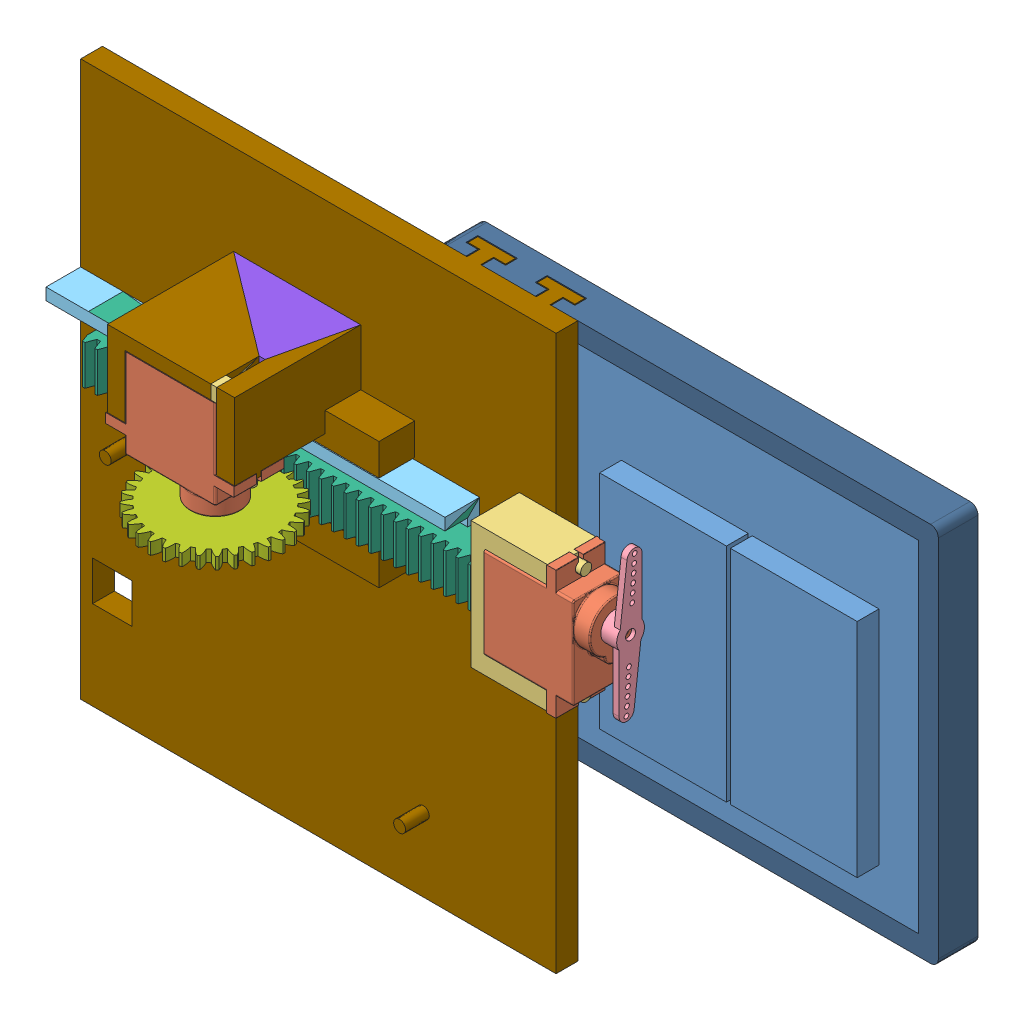
SolidWorks assembly 装配体3, configuration 默认. Lengths in mm.
Overall size (211 140 65.05).
16 component instances, 13 part files, 28 mates.
Components (placement in the parent):
- 底座框架-1: 底座框架 [默认] at (39.9503 -6.2034 133) size (126 96 10) (hidden)
- 活动底板-1: 活动底板 [默认] at origin size (120 140 23.5) (hidden)
- 开关建模-1: 开关建模 [默认] at (39.9503 -6.2034 133) size (86 86 15.5)
- SG90_Model_B.step-1: SG90_Model_B.step [默认] at (-8.8492 -13.8034 144.6) x (0 0 1) z (-1 0 0) size (12.61 32.4 29.2)
- 舵机外壳-1: 舵机外壳 [默认] at (-8.8492 -13.7034 138.5) x (0 -1 0) z (0 0 1) size (32.1 23 12.2)
- rack spur rectangular_gb-1: rack spur rectangular_gb [GB - Rack-spur - rectangular 1M 20PA 10mmFW 10mmPH 100mmL---SAll] at (-12.3492 -8.7034 138.5) x (-1 0 0) z (0 1 0) size (100 11 10) (hidden)
- SG90_Arm_04_Custom.step-1: SG90_Arm_04_Custom.step [默认] at (21.8508 -8.6034 144.6) x (0 0.059323 0.998239) z (-1 0 0) size (7 37 4)
- 放线槽-1: 放线槽 [默认] at (0 0 138.5) size (100.7 5 8.75)
- 带槽齿条-1: 带槽齿条 [默认] at (-32.6473 0.8988 -33.444) size (100 15 11)
- SG90_Model_B.step-2: SG90_Model_B.step [默认] at (-68.502 15.4966 164.249) x (0 0 1) z (0 1 0) size (12.61 32.4 29.2)
- spur gear_gb-1: spur gear_gb [GB - Spur gear 1M 32T 20PA 3FW ---S32A75H50L5.0N] at (-63.302 -12.2034 164.249) x (0 -1 0) z (0.619613 0 -0.784907) size (3 33.89 33.89)
- 舵机外壳-2: 舵机外壳 [默认] at (-68.402 15.4966 158.149) x (-1 0 0) z (0 0 1) size (32.1 23 12.2)
- 底板和舵机座连接体-1: 底板和舵机座连接体 [默认] at origin size (32.1 19.3 19.65)
- 底板和舵机连接重组^装配体3-1: 底板和舵机连接重组^装配体3 [默认] at origin size (120 140 46.35) (virtual)
- 带槽舵机壳齿条-1: 带槽舵机壳齿条 [默认] at origin size (123 32.1 12.2) (hidden)
- 底座框架-2: 底座框架 [默认] at (39.9503 -6.2034 133) size (126 96 10)
Mates (geometry in assembly coordinates):
- 重合1: coincident aligned: plane of 底座框架-1 through (39.9503 -6.2034 123) normal (0 0 -1); plane of 开关建模-1 through (39.9503 -6.2034 123) normal (0 0 -1)
- 重合3: coincident anti-aligned: plane of 底座框架-1 through (82.9503 36.7966 123) normal (-1 0 0); plane of 开关建模-1 through (82.9503 36.7966 1.3776) normal (1 0 0)
- 重合4: coincident anti-aligned: plane of 底座框架-1 through (-3.0497 36.7966 123) normal (0 -1 0); plane of 开关建模-1 through (-3.0497 36.7966 1.3776) normal (0 1 0)
- 同心1: concentric anti-aligned: circle of SG90_Model_B.step-1; circle of 舵机外壳-1
- 重合5: coincident anti-aligned: plane of SG90_Model_B.step-1 through (-8.8492 -13.8034 144.6) normal (-1 0 0); plane of 舵机外壳-1 through (-8.8492 -2.1534 150.7) normal (1 0 0)
- 宽度1: width aligned: plane of rack spur rectangular_gb-1 through (-12.3492 -8.7034 149.5) normal (0 1 0); plane of 舵机外壳-1 through (-12.3492 -18.7034 149.5) normal (0 -1 0); plane of rack spur rectangular_gb-1 through (-13.3492 2.3466 150.7) normal (0 1 0); plane of 舵机外壳-1 through (-13.3492 -29.7534 150.7) normal (0 -1 0)
- 重合6: coincident aligned: plane of rack spur rectangular_gb-1 through (-12.3492 -18.7034 138.5) normal (0 0 -1); plane of 舵机外壳-1 through (-8.8492 -13.7034 138.5) normal (0 0 -1)
- 重合7: coincident anti-aligned: plane of 舵机外壳-1 through (-12.3492 14.5875 150.7) normal (-1 0 0); plane of rack spur rectangular_gb-1 through (-12.3492 -18.7034 138.5) normal (1 0 0)
- 平行2: parallel anti-aligned: plane of SG90_Model_B.step-1 through (-8.8492 -25.3034 150.9) normal (0 -1 0); plane of 舵机外壳-1 through (-8.8492 -25.2534 150.7) normal (0 1 0)
- 重合10: coincident anti-aligned: plane of 活动底板-1 through (39.9503 -6.2034 138.5) normal (0 0 1); plane of 舵机外壳-1 through (-8.8492 -13.7034 138.5) normal (0 0 -1)
- 同心2: concentric anti-aligned: circle of SG90_Model_B.step-1; circle of SG90_Arm_04_Custom.step-1
- 重合11: coincident anti-aligned: plane of SG90_Model_B.step-1 through (17.8508 -9.5534 144.6) normal (1 0 0); plane of SG90_Arm_04_Custom.step-1 through (17.8508 -8.6034 144.6) normal (-1 0 0)
- 宽度3: width anti-aligned: plane of 带槽齿条-1 through (-12.3492 -18.7034 149.5) normal (0 -1 0); plane of 带槽齿条-1 through (-12.3492 -8.7034 149.5) normal (0 1 0); plane of 舵机外壳-1 through (-13.3492 2.3466 150.7) normal (0 1 0); plane of 舵机外壳-1 through (-13.3492 -29.7534 150.7) normal (0 -1 0)
- 重合17: coincident anti-aligned: plane of 舵机外壳-1 through (-12.3492 14.5875 150.7) normal (-1 0 0); plane of 带槽齿条-1 through (-12.3492 -18.7034 138.5) normal (1 0 0)
- 宽度6: width anti-aligned: plane of 带槽齿条-1 through (-2.2714 -3.7034 147.25) normal (0 1 0); plane of 带槽齿条-1 through (-12.3492 -18.7034 149.5) normal (0 -1 0); plane of 活动底板-1 through (-98.2551 -3.2034 147.5) normal (0 -1 0); plane of 活动底板-1 through (-98.2551 -19.2034 147.5) normal (0 1 0)
- 重合19: coincident anti-aligned: plane of 活动底板-1 through (39.9503 -6.2034 138.5) normal (0 0 1); plane of 带槽齿条-1 through (-12.3492 -18.7034 138.5) normal (0 0 -1)
- 同心10: concentric anti-aligned: circle of SG90_Model_B.step-2; circle of GB - Spur gear 1M 32T 20PA 3FW ---S32A75H50L5.0N-1
- 距离2: distance = 1 mm anti-aligned: plane of SG90_Model_B.step-2 through (-64.252 -11.2034 164.249) normal (0 -1 0); plane of GB - Spur gear 1M 32T 20PA 3FW ---S32A75H50L5.0N-1 through (-63.302 -12.2034 164.249) normal (0 1 0)
- 宽度7: width aligned: plane of SG90_Model_B.step-2 through (-57.002 15.4966 157.949) normal (1 0 0); plane of SG90_Model_B.step-2 through (-80.002 15.4966 170.549) normal (-1 0 0); plane of 活动底板-1 through (-38.7488 4.7966 147.5) normal (1 0 0); plane of 活动底板-1 through (-98.2551 4.7966 147.5) normal (-1 0 0)
- 相切1: tangent anti-aligned: plane of 带槽舵机壳齿条-1 through (-12.3492 -18.7034 149.5) normal (0 0 1); cylinder of spur gear_gb-1 through (-63.302 -15.2034 164.249) axis (0 1 0) radius 14.749
- 宽度8: width aligned: plane of spur gear_gb-1 through (-63.302 -12.2034 164.249) normal (0 1 0); plane of spur gear_gb-1 through (-63.302 -15.2034 164.249) normal (0 -1 0); plane of 带槽齿条-1 through (-12.3492 -8.7034 149.5) normal (0 1 0); plane of 带槽齿条-1 through (-12.3492 -18.7034 149.5) normal (0 -1 0)
- RackPinionMate1: rack pinion = 29.498 mm: line of 带槽齿条-1 through (-12.3492 -18.7034 138.5) axis (-1 0 0); circle of GB - Spur gear 1M 32T 20PA 3FW ---S32A75H50L5.0N-1
- 同心11: concentric anti-aligned: circle of SG90_Model_B.step-2; circle of 舵机外壳-2
- 重合23: coincident anti-aligned: plane of SG90_Model_B.step-2 through (-68.502 15.4966 164.249) normal (0 1 0); plane of 舵机外壳-2 through (-56.852 15.4966 170.349) normal (0 -1 0)
- 平行5: parallel anti-aligned: plane of 活动底板-1 through (39.9503 -6.2034 138.5) normal (0 0 1); plane of SG90_Model_B.step-2 through (-80.002 15.4966 157.949) normal (0 0 -1)
- 重合24: coincident: plane of 开关建模-1 through (-3.0497 36.7966 1.3776) normal (0 1 0); plane of 底座框架-2 through (-3.0497 36.7966 123) normal (0 -1 0)
- 重合25: coincident: plane of 开关建模-1 through (39.9503 -6.2034 123) normal (0 0 -1); plane of 底座框架-2 through (39.9503 -6.2034 123) normal (0 0 -1)
- 重合26: coincident: line of 开关建模-1 through (82.9503 -49.2034 133) axis (0 1 0); plane of 底座框架-2 through (82.9503 36.7966 123) normal (-1 0 0)
